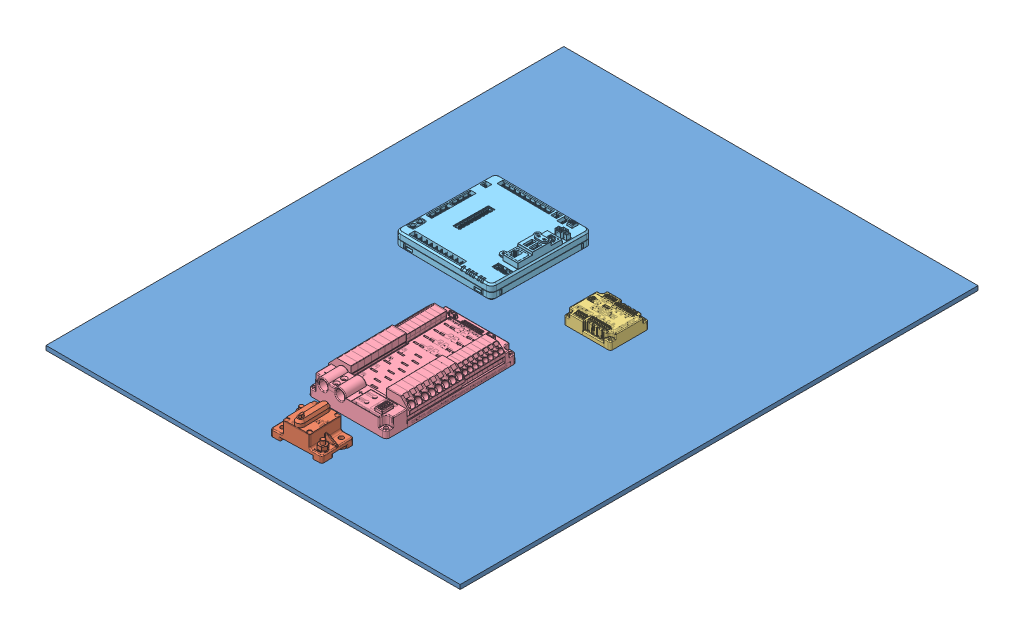
SolidWorks assembly Assem1, configuration Default. Lengths in mm.
Overall size (609.6 48.5 762).
5 component instances, 5 part files, 5 mates.
Components (placement in the parent):
- Test Bench-1: Test Bench [Default] at (-273.2159 2.1793 360.6959) size (609.6 6.35 762)
- Breaker-1: Breaker [Default] at (43.4766 13.3553 285.6853) x (0.999587 0 -0.028744) z (0.028744 0 0.999587) size (73.72 42.2 48.95)
- PCM-1: PCM [Default] at (114.8555 12.9743 -75.6687) size (69.09 27.65 56.9)
- PDP-1: PDP [Default] at (40.1977 15.8059 130.3838) x (0.000009 0.017452 -0.999848) z (1 -0.000524 0) size (192.68 36.15 120.93)
- Roborio-1: Roborio [Default] at (-71.0895 18.1813 -95.6951) x (-0.010874 0 0.999941) z (0 1 0) size (146.27 143.19 36.83)
Mates (geometry in assembly coordinates):
- Coincident1: coincident aligned: plane of Test Bench-1 through (-273.2159 8.5293 360.6959) normal (0 1 0); plane of Roborio-1 through (-142.2525 8.5293 -169.9853) normal (0 1 0)
- Coincident2: coincident anti-aligned: plane of Test Bench-1 through (-273.2159 8.5293 360.6959) normal (0 1 0); plane of Breaker-1 through (11.5001 8.5293 269.1121) normal (0 -1 0)
- Coincident3: coincident: plane of Test Bench-1 through (-273.2159 8.5293 360.6959) normal (0 1 0); plane of PDP-1 through (97.5991 10.7027 38.257) normal (-0.000524 -0.999848 -0.017452)
- Parallel2: parallel: plane of Test Bench-1 through (-273.2159 8.5293 360.6959) normal (0 0 1); plane of PDP-1 through (97.5973 7.3399 230.9121) normal (0 0 1)
- Coincident4: coincident anti-aligned: plane of Test Bench-1 through (-273.2159 8.5293 360.6959) normal (0 1 0); plane of PCM-1 through (84.4263 8.5293 -99.9765) normal (0 -1 0)
